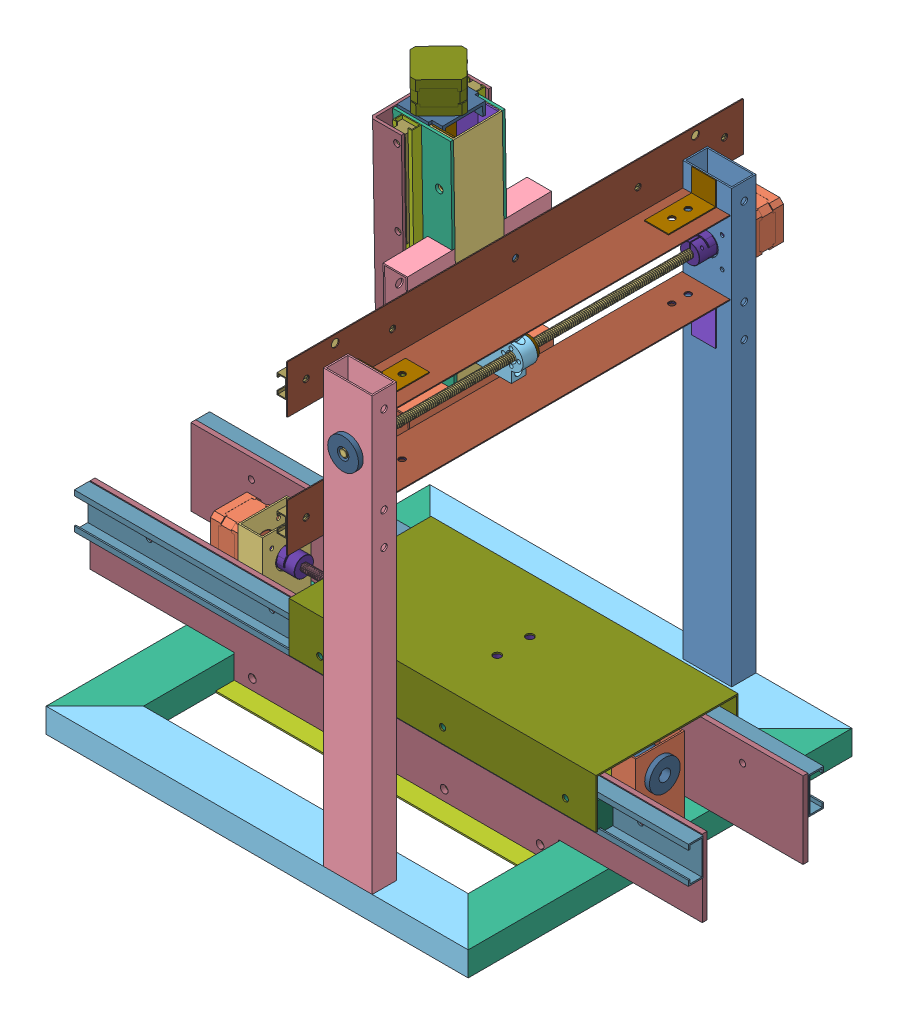
SolidWorks assembly cnc vr 3.0, configuration Predeterminado. Lengths in mm.
Overall size (640 636.76 475).
65 component instances, 40 part files, 107 mates.
Components (placement in the parent):
- Ensamblaje1-1: Ensamblaje1 [Predeterminado] at (-134.9886 -175.6891 185.1886) x (1 0 0) z (0 -1 0) size (445 405 475.4)
  - soporte vertical base eje Y (motor)-1: soporte vertical base eje Y (motor) [Predeterminado] at (289.2 12.7 -12.7) x (1 0 0) z (0 0 -1) size (50.8 25.4 450)
  - soporte rodamiento eje X-1: soporte rodamiento eje X [Predeterminado] at (401.9 200 -12.7) x (0 1 0) z (0 0 -1) size (50.8 25.4 85)
  - soporte motor eje X-1: soporte motor eje X [Predeterminado] at (12.7 200 -12.7) x (0 1 0) z (0 0 -1) size (50.8 25.4 90)
  - soporte vertical base eje Y (rodamiento)-1: soporte vertical base eje Y (rodamiento) [Predeterminado] at (289.2 387.3 -12.7) x (1 0 0) z (0 0 -1) size (50.8 25.4 450)
  - base 2x1 laterales-1: base 2x1 laterales [Predeterminado] at (-25.4 374.6 0) x (0 -1 0) z (1 0 0) size (50.8 25.4 440)
  - base 2x1 frontal-1: base 2x1 frontal [Predeterminado] at (389.2 0 0) x (-1 0 0) z (0 0 -1) size (50.8 400 25.4)
  - soporte transvarsal base-1: soporte transvarsal base [Predeterminado] at (25.4 151.5 12.7) x (0 -1 0) z (1 0 0) size (25.4 25.4 338.4)
  - base 2x1 laterales-2: base 2x1 laterales [Predeterminado] at (414.6 25.4 0) x (0 1 0) z (-1 0 0) size (50.8 25.4 440)
  - soporte transvarsal base-2: soporte transvarsal base [Predeterminado] at (363.8 248.5 12.7) x (0 1 0) z (-1 0 0) size (25.4 25.4 338.4)
  - junta eje y-1: junta eje y [Predeterminado] at (298.8 26.4 -359.7) x (0 0 1) z (-1 0 0) size (50 50 25)
  - junta eje2 y-1: junta eje2 y [Predeterminado] at (273.8 26.4 -438.7) x (0 0 -1) z (1 0 0) size (25 50 25)
  - junta eje2 y-2: junta eje2 y [Predeterminado] at (298.8 373.6 -438.7) x (0 0 -1) z (-1 0 0) size (25 50 25)
  - junta eje y-2: junta eje y [Predeterminado] at (273.8 373.6 -359.7) x (0 0 1) z (1 0 0) size (50 50 25)
  - asiento de rodamiento-1: asiento de rodamiento [Predeterminado] at (384.2 200 -72.7) x (0 -1 0) z (1 0 0) size (32 32 35.4)
  - asiento de rodamiento-2: asiento de rodamiento [Predeterminado] at (289.2 369.6 -400.2) x (1 0 0) z (0 1 0) size (32 32 35.4)
  - base 2x1 frontal-2: base 2x1 frontal [Predeterminado] at origin size (50.8 400 25.4)
- Soporte eje Y^cnc vr 3.0-2: Soporte eje Y^cnc vr 3.0 [Predeterminado] at (127.8114 261.0109 147.6886) size (60 175 475) (virtual)
  - soporte eje Y-1: soporte eje Y [Predeterminado] at origin size (50 50 475)
  - soporte eje Y-2: soporte eje Y [Predeterminado] at (0 -75 475) x (1 0 0) z (0 0 -1) size (50 50 475)
  - riel eje Y-1: riel eje Y [Predeterminado] at (0 35 0) x (-1 0 0) z (0 0 1) size (10 20 475)
  - riel eje Y-2: riel eje Y [Predeterminado] at (0 -90 0) x (-1 0 0) z (0 0 1) size (10 20 475)
- base lateral-1: base lateral [Predeterminado] at (228.6114 -186.4891 330.1886) size (638 105 5)
- base lateral-2: base lateral [Predeterminado] at (228.6114 -186.4891 435.1886) size (638 105 5)
- Riel eje x-1: Riel eje x [Predeterminado] at (-260.3886 -101.4891 322.4386) x (0 0 -1) z (1 0 0) size (15.5 38 640)
- Riel eje x-2: Riel eje x [Predeterminado] at (379.6114 -101.4891 447.9386) x (0 0 1) z (-1 0 0) size (15.5 38 640)
- Riel interior eje x-1: Riel interior eje x [Predeterminado] at (-33.1112 -101.4891 322.4386) x (0 0 -1) z (1 0 0) size (16 35 320)
- Riel interior eje x-2: Riel interior eje x [Predeterminado] at (286.8888 -101.4891 447.9386) x (0 0 1) z (-1 0 0) size (16 35 320)
- eje x-1: eje x [Predeterminado] at (-33.1112 -91.438 385.0405) x (0 0 -1) z (1 0 0) size (148 51.5 320)
- nut soporte-1: nut soporte [Predeterminado] at (119.3888 -102.8891 385.1886) x (0 0 -1) z (1 0 0) size (48 48.9 15)
- nut-2: nut [Predeterminado] at (115.3888 -102.8891 385.1886) x (0 0 -1) z (1 0 0) size (21 21 15.64)
- Base eje Y^cnc vr 3.0-2: Base eje Y^cnc vr 3.0 [Predeterminado] at (126.8114 170.0109 331.1531) x (-1 0 0) z (0 0 1) size (76.9 278.42 152.92) (virtual)
  - Riel interior eje Y-1: Riel interior eje Y [Predeterminado] at origin size (12 18 150)
  - Riel interior eje Y-2: Riel interior eje Y [Predeterminado] at (0 -125 2.0819) size (12 18 150)
  - componente 1 base eje y-1: componente 1 base eje y [Predeterminado] at (24.7 8.7522 0.002) x (0 -0.999863 0.016522) z (0 0.016522 0.999863) size (50.8 25.4 150)
  - componente 2 base eje y-1: componente 2 base eje y [Predeterminado] at (24.7 -241.3744 79.1455) x (0 -0.016522 -0.999863) z (0 0.999863 -0.016522) size (50.8 25.4 226)
  - componente 3 base eje y-1: componente 3 base eje y [Predeterminado] at (24.7 -118.2305 2.1004) x (0 -0.999863 0.016522) z (0 0.016522 0.999863) size (50.8 25.4 49.6)
  - componente 3 base eje y-2: componente 3 base eje y [Predeterminado] at (24.7 -115.7522 152.0799) x (0 -0.999863 0.016522) z (0 -0.016522 -0.999863) size (50.8 25.4 49.6)
  - nut soporte eje Y-1: nut soporte eje Y [Predeterminado] at (-27 -54.0239 68.5486) x (0 -0.999863 0.016522) z (0 0.016522 0.999863) size (48 51.5 15)
  - nut-1: nut [Predeterminado] at (-27 -54.09 64.5491) x (-1 0 0) z (0 0.016522 0.999863) size (21 21 15.64)
- soporte eje Z-3: soporte eje Z [Predeterminado] at (114.8114 262.8748 379.4406) x (0 0.999863 0.016522) z (0 -0.016522 0.999863) size (276 60.4 3)
- soporte eje Z-4: soporte eje Z [Predeterminado] at (114.8114 261.9859 433.2333) x (0 0.999863 0.016522) z (0 -0.016522 0.999863) size (276 60.4 3)
- riel eje Z-3: riel eje Z [Predeterminado] at (64.4114 411.8545 381.9024) x (0 0.016522 -0.999863) z (0 -0.999863 -0.016522) size (10 20 276)
- riel eje Z-4: riel eje Z [Predeterminado] at (64.4114 134.9537 434.1345) x (0 -0.016522 0.999863) z (0 0.999863 0.016522) size (10 20 276)
- soporte eje Z motor (derecho)-1: soporte eje Z motor (derecho) [Predeterminado] at (90.9114 412.2801 386.4101) x (1 0 0) z (0 -0.999863 -0.016522) size (22.4 23.9 60)
- soporte eje Z motor (izq)-1: soporte eje Z motor (izq) [Predeterminado] at (90.9114 351.4985 433.2122) x (1 0 0) z (0 0.999863 0.016522) size (22.4 23.9 60)
- soporte eje z motor frontal-1: soporte eje z motor frontal [Predeterminado] at (100.4114 415.2549 387.9594) x (0 -0.016522 0.999863) z (0 -0.999863 -0.016522) size (52 44 13)
- soporte eje Z rodamiento-1: soporte eje Z rodamiento [Predeterminado] at (114.8114 135.0526 379.7288) x (0 -0.016522 0.999863) z (1 0 0) size (52 3 58.4)
- Riel interior eje Z-1: Riel interior eje Z [Predeterminado] at (83.4114 407.1 439.6318) x (0 -0.016522 0.999863) z (0 -0.999863 -0.016522) size (12 18 100)
- Riel interior eje Z-2: Riel interior eje Z [Predeterminado] at (83.4114 308.0852 379.1876) x (0 0.016522 -0.999863) z (0 0.999863 0.016522) size (12 18 100)
- eje Z-1: eje Z [Predeterminado] at (84.4114 408.2698 368.8414) x (0 -0.016522 0.999863) z (0 -0.999863 -0.016522) size (88.8 38 276)
- nut soporte eje Z-1: nut soporte eje Z [Predeterminado] at (74.4114 315.0984 408.7075) x (0 -0.016522 0.999863) z (0 -0.999863 -0.016522) size (48 37.5 15)
- nut-1: nut [Predeterminado] at (74.4114 319.0978 408.7735) x (1 0 0) z (0 -0.999863 -0.016522) size (21 21 15.64)
- asiento de rodamiento eje z-1: asiento de rodamiento eje z [Predeterminado] at (74.4114 133.6232 405.7087) x (1 0 0) z (0 0.999863 0.016522) size (28 28 15)
- nema 17-1: nema 17 [Predeterminado] at (74.4114 431.3825 410.629) x (0 -0.999863 -0.016522) z (0.709494 0.011643 -0.704615) size (56.5 42 42)
- CPJC20-RD-5-8-1: CPJC20-RD-5-8 [Default] at (74.4114 401.3866 410.1333) x (0 -0.999863 -0.016522) z (0.927601 -0.006172 0.373521) size (30 20 20)
- tornillo de potencia eje Z-2: tornillo de potencia eje Z [Predeterminado] at (74.4114 131.6234 405.6756) x (-0.961589 -0.004535 0.274455) z (0 0.999863 0.016522) size (9.26 8.06 251.99)
- rodamiento skf 8X22-1: rodamiento skf 8X22 [Predeterminado] at (74.4114 137.6226 405.7748) x (1 0 0) z (0 -0.999863 -0.016522) size (22 22 8)
- nema 17-2-1: nema 17-2 [Predeterminado] at (154.2114 224.5109 168.6886) x (0 0 1) z (-1 0 0) size (56.5 42 42)
- CPJC20-RD-5-8-2: CPJC20-RD-5-8 [Default] at (154.2114 224.5109 198.6886) x (0 0 1) z (-1 0 0) size (30 20 20)
- tornillo de potencia eje Y-1: tornillo de potencia eje Y [Predeterminado] at (154.2114 224.5109 590.1886) x (1 0 0) z (0 0 -1) size (9.26 8.02 374.13)
- nema 17-2-2: nema 17-2 [Predeterminado] at (-151.4886 -102.9891 385.1886) size (56.5 42 42)
- CPJC20-RD-5-8-3: CPJC20-RD-5-8 [Default] at (-121.4886 -102.9891 385.1886) x (1 0 0) z (0 0.52607 -0.850441) size (30 20 20)
- tornillo de potencia-1: tornillo de potencia [Predeterminado] at (278.5114 -102.8891 385.1886) x (0 -0.883869 0.467735) z (-1 0 0) size (9.26 8.1 385.02)
- rodamiento skf 8X22-2: rodamiento skf 8X22 [Predeterminado] at (264.2114 -102.9891 385.1886) x (0 0 -1) z (1 0 0) size (22 22 8)
Mates (geometry in assembly coordinates):
- Concéntrica55: concentric aligned: cylinder of Ensamblaje1-1/junta eje2 y-2 through (151.3114 264.0109 542.7886) axis (0 -1 0) radius 3.2; cylinder of Soporte eje Y^cnc vr 3.0-2/soporte eje Y-1 through (151.3114 263.0109 542.7886) axis (0 -1 0) radius 3.2
- Concéntrica56: concentric aligned: cylinder of Ensamblaje1-1/junta eje2 y-1 through (151.3114 264.0109 227.5886) axis (0 -1 0) radius 3.2; cylinder of Soporte eje Y^cnc vr 3.0-2/soporte eje Y-1 through (151.3114 263.0109 227.5886) axis (0 -1 0) radius 3.2
- Coincidente86: coincident anti-aligned: plane of Ensamblaje1-1/junta eje2 y-1 through (163.8114 262.0109 210.5886) normal (0 -1 0); plane of Soporte eje Y^cnc vr 3.0-2/soporte eje Y-1 through (128.8114 262.0109 622.6886) normal (0 1 0)
- Concéntrica57: concentric aligned: cylinder of Ensamblaje1-1/junta eje y-2 through (151.3114 183.0109 542.7886) axis (0 1 0) radius 3.2; cylinder of Soporte eje Y^cnc vr 3.0-2/soporte eje Y-2 through (151.3114 184.0109 542.7886) axis (0 1 0) radius 3.2
- Concéntrica58: concentric aligned: cylinder of Ensamblaje1-1/junta eje y-1 through (151.3114 183.0109 227.5886) axis (0 1 0) radius 3.2; cylinder of Soporte eje Y^cnc vr 3.0-2/soporte eje Y-2 through (151.3114 184.0109 227.5886) axis (0 1 0) radius 3.2
- Coincidente87: coincident anti-aligned: plane of Ensamblaje1-1/junta eje y-1 through (138.8114 185.0109 210.5886) normal (0 1 0); plane of Soporte eje Y^cnc vr 3.0-2/soporte eje Y-2 through (128.8114 185.0109 147.6886) normal (0 -1 0)
- Coincidente104: coincident aligned: plane of soporte eje Z motor (derecho)-1 through (90.9114 412.2801 386.4101) normal (0 0.999863 0.016522); plane of soporte eje Z motor (izq)-1 through (90.9114 411.4903 434.2035) normal (0 0.999863 0.016522)
- Coincidente105: coincident anti-aligned: plane of soporte eje Z motor (derecho)-1 through (90.9114 351.8934 409.3155) normal (0 -0.016522 0.999863); plane of soporte eje Z motor (izq)-1 through (90.9114 411.8852 410.3068) normal (0 0.016522 -0.999863)
- Coincidente106: coincident aligned: plane of soporte eje Z motor (derecho)-1 through (92.4114 352.2635 386.9185) normal (1 0 0); plane of soporte eje Z motor (izq)-1 through (92.4114 411.5151 432.7038) normal (1 0 0)
- Concéntrica67: concentric anti-aligned: cylinder of soporte eje Z-3 through (74.4114 401.8063 384.7368) axis (0 0.016522 -0.999863) radius 3.2; cylinder of riel eje Z-3 through (74.4114 401.8889 379.7375) axis (0 -0.016522 0.999863) radius 3.2
- Concéntrica68: concentric anti-aligned: cylinder of soporte eje Z-3 through (74.4114 145.8412 380.5071) axis (0 0.016522 -0.999863) radius 3.2; cylinder of riel eje Z-3 through (74.4114 145.9238 375.5078) axis (0 -0.016522 0.999863) radius 3.2
- Coincidente100: coincident anti-aligned: plane of soporte eje Z-3 through (114.8114 262.8748 379.4406) normal (0 0.016522 -0.999863); plane of riel eje Z-3 through (64.4114 135.8922 377.3423) normal (0 -0.016522 0.999863)
- Concéntrica69: concentric aligned: cylinder of soporte eje Z-4 through (74.4114 400.9174 438.5294) axis (0 0.016522 -0.999863) radius 3.2; cylinder of riel eje Z-4 through (74.4114 400.8843 440.5292) axis (0 0.016522 -0.999863) radius 3.2
- Concéntrica70: concentric aligned: cylinder of soporte eje Z-4 through (74.4114 144.9523 434.2998) axis (0 0.016522 -0.999863) radius 3.2; cylinder of riel eje Z-4 through (74.4114 144.9193 436.2995) axis (0 0.016522 -0.999863) radius 3.2
- Coincidente101: coincident anti-aligned: plane of soporte eje Z-4 through (114.8114 261.9364 436.2329) normal (0 -0.016522 0.999863); plane of riel eje Z-4 through (64.4114 410.916 438.6947) normal (0 0.016522 -0.999863)
- Coincidente120: coincident anti-aligned: plane of soporte eje Z motor (derecho)-1 through (92.4114 352.2635 386.9185) normal (0 -0.016522 0.999863); plane of soporte eje z motor frontal-1 through (100.4114 412.2553 387.9099) normal (0 0.016522 -0.999863)
- Coincidente121: coincident anti-aligned: plane of soporte eje Z motor (izq)-1 through (92.4114 411.5151 432.7038) normal (1 0 0); plane of soporte eje z motor frontal-1 through (92.4114 401.5164 432.5385) normal (-1 0 0)
- Coincidente122: coincident anti-aligned: plane of soporte eje Z motor (izq)-1 through (90.9114 411.4903 434.2035) normal (0 0.999863 0.016522); plane of soporte eje z motor frontal-1 through (100.4114 412.2553 387.9099) normal (0 -0.999863 -0.016522)
- Coincidente127: coincident anti-aligned: plane of Soporte eje Y^cnc vr 3.0-2/riel eje Y-2 through (126.8114 170.0109 622.6886) normal (-1 0 0); plane of Base eje Y^cnc vr 3.0-2/Riel interior eje Y-1 through (126.8114 170.0109 481.1531) normal (1 0 0)
- Coincidente128: coincident anti-aligned: plane of Soporte eje Y^cnc vr 3.0-2/riel eje Y-2 through (118.8114 170.0109 622.6886) normal (0 -1 0); plane of Base eje Y^cnc vr 3.0-2/Riel interior eje Y-1 through (118.8114 170.0109 481.1531) normal (0 1 0)
- Coincidente129: coincident anti-aligned: plane of Soporte eje Y^cnc vr 3.0-2/riel eje Y-1 through (126.8114 295.0109 622.6886) normal (-1 0 0); plane of Base eje Y^cnc vr 3.0-2/Riel interior eje Y-2 through (126.8114 295.0109 483.235) normal (1 0 0)
- Coincidente130: coincident anti-aligned: plane of Soporte eje Y^cnc vr 3.0-2/riel eje Y-1 through (118.8114 295.0109 622.6886) normal (0 -1 0); plane of Base eje Y^cnc vr 3.0-2/Riel interior eje Y-2 through (118.8114 295.0109 483.235) normal (0 1 0)
- Coincidente131: coincident anti-aligned: plane of Base eje Y^cnc vr 3.0-2/componente 1 base eje y-1 through (114.8114 133.3839 480.715) normal (0 -0.999863 -0.016522); plane of soporte eje Z rodamiento-1 through (114.8114 135.0526 379.7288) normal (0 0.999863 0.016522)
- Coincidente132: coincident aligned: plane of Base eje Y^cnc vr 3.0-2/componente 1 base eje y-1 through (114.8114 133.3839 480.715) normal (1 0 0); plane of soporte eje Z rodamiento-1 through (114.8114 132.053 379.6792) normal (1 0 0)
- Coincidente133: coincident anti-aligned: plane of Base eje Y^cnc vr 3.0-2/componente 2 base eje y-1 through (90.9114 185.0212 430.4613) normal (1 0 0); plane of soporte eje Z motor (izq)-1 through (90.9114 411.4903 434.2035) normal (-1 0 0)
- Coincidente134: coincident anti-aligned: plane of Base eje Y^cnc vr 3.0-2/componente 2 base eje y-1 through (90.9114 185.0212 430.4613) normal (0 0.016522 -0.999863); plane of soporte eje Z motor (izq)-1 through (90.9114 411.4903 434.2035) normal (0 -0.016522 0.999863)
- Concéntrica85: concentric aligned: cylinder of Base eje Y^cnc vr 3.0-2/componente 2 base eje y-1 through (102.1114 361.469 435.0772) axis (0 0.016522 -0.999863) radius 4; cylinder of soporte eje Z-4 through (102.1114 361.4228 437.8768) axis (0 0.016522 -0.999863) radius 4
- Concéntrica86: concentric aligned: cylinder of Base eje Y^cnc vr 3.0-2/componente 2 base eje y-1 through (102.1114 223.4879 432.7971) axis (0 0.016522 -0.999863) radius 4; cylinder of soporte eje Z-4 through (102.1114 223.4416 435.5968) axis (0 0.016522 -0.999863) radius 4
- Coincidente135: coincident anti-aligned: plane of Base eje Y^cnc vr 3.0-2/componente 2 base eje y-1 through (89.4114 184.9964 431.9611) normal (0 -0.016522 0.999863); plane of soporte eje Z-4 through (114.8114 261.9859 433.2333) normal (0 0.016522 -0.999863)
- Coincidente136: coincident anti-aligned: plane of Base eje Y^cnc vr 3.0-2/componente 2 base eje y-1 through (89.4114 185.8358 381.168) normal (0 0.016522 -0.999863); plane of soporte eje Z-3 through (114.8114 262.8253 382.4402) normal (0 -0.016522 0.999863)
- Concéntrica87: concentric anti-aligned: cylinder of Base eje Y^cnc vr 3.0-2/componente 2 base eje y-1 through (102.1114 361.469 435.0772) axis (0 0.016522 -0.999863) radius 4; cylinder of soporte eje Z motor (izq)-1 through (102.1114 361.5302 431.3777) axis (0 -0.016522 0.999863) radius 4
- Distancia5: distance = 26 mm anti-aligned: plane of Base eje Y^cnc vr 3.0-2/componente 2 base eje y-1; plane of soporte eje Z rodamiento-1
- Coincidente137: coincident anti-aligned: plane of Base eje Y^cnc vr 3.0-2/componente 3 base eje y-1 through (89.4114 262.0254 382.427) normal (-1 0 0); plane of soporte eje Z-3 through (89.4114 312.8184 383.2663) normal (1 0 0)
- Coincidente138: coincident anti-aligned: plane of Base eje Y^cnc vr 3.0-2/componente 3 base eje y-1 through (114.8114 312.8184 383.2663) normal (0 0.999863 0.016522); plane of soporte eje Z-3 through (114.8114 312.8184 383.2663) normal (0 -0.999863 -0.016522)
- Coincidente139: coincident anti-aligned: plane of riel eje Z-4 through (65.4114 410.8995 439.6945) normal (0 -0.016522 0.999863); plane of Riel interior eje Z-1 through (83.4114 307.1137 437.9795) normal (0 0.016522 -0.999863)
- Coincidente140: coincident anti-aligned: plane of riel eje Z-4 through (65.4114 410.7673 447.6934) normal (1 0 0); plane of Riel interior eje Z-1 through (65.4114 307.1137 437.9795) normal (-1 0 0)
- Coincidente141: coincident anti-aligned: plane of riel eje Z-3 through (65.4114 135.9087 376.3424) normal (0 0.016522 -0.999863); plane of Riel interior eje Z-2 through (83.4114 408.0715 380.8398) normal (0 -0.016522 0.999863)
- Coincidente142: coincident anti-aligned: plane of riel eje Z-3 through (83.4114 135.9087 376.3424) normal (-1 0 0); plane of Riel interior eje Z-2 through (83.4114 408.2037 372.8409) normal (1 0 0)
- Concéntrica88: concentric aligned: cylinder of Riel interior eje Z-2 through (74.4114 398.172 374.6754) axis (0 0.016522 -0.999863) radius 3.2; cylinder of eje Z-1 through (74.4114 396.8337 455.6643) axis (0 0.016522 -0.999863) radius 3.2
- Concéntrica89: concentric anti-aligned: cylinder of Riel interior eje Z-1 through (74.4114 317.0132 444.1439) axis (0 -0.016522 0.999863) radius 3.2; cylinder of eje Z-1 through (74.4114 316.8446 454.3425) axis (0 0.016522 -0.999863) radius 3.2
- Coincidente144: coincident anti-aligned: plane of Riel interior eje Z-2 through (68.4114 408.2698 368.8414) normal (0 0.016522 -0.999863); plane of eje Z-1 through (84.4114 132.3075 364.2813) normal (0 -0.016522 0.999863)
- Concéntrica90: concentric aligned: cylinder of eje Z-1 through (50.4114 307.3185 425.5812) axis (-1 0 0) radius 4; cylinder of nut soporte eje Z-1 through (86.9124 307.3185 425.5812) axis (-1 0 0) radius 4
- Concéntrica92: concentric aligned: cylinder of eje Z-1 through (50.4114 307.8803 391.5859) axis (-1 0 0) radius 4; cylinder of nut soporte eje Z-1 through (86.9124 307.8803 391.5859) axis (-1 0 0) radius 4
- Coincidente145: coincident anti-aligned: plane of eje Z-1 through (49.4114 132.3075 364.2813) normal (1 0 0); plane of nut soporte eje Z-1 through (49.4114 300.497 384.4629) normal (-1 0 0)
- Concéntrica93: concentric aligned: cylinder of nut soporte eje Z-1 through (74.4114 300.1004 408.4596) axis (0 0.999863 0.016522) radius 5.5; cylinder of nut-1 through (74.4114 306.0996 408.5588) axis (0 0.999863 0.016522) radius 5.5
- Concéntrica94: concentric aligned: cylinder of nut soporte eje Z-1 through (74.4114 299.9683 416.4585) axis (0 0.999863 0.016522) radius 2; cylinder of nut-1 through (74.4114 314.9662 416.7064) axis (0 0.999863 0.016522) radius 2
- Coincidente146: coincident anti-aligned: plane of nut soporte eje Z-1 through (74.4114 315.0984 408.7075) normal (0 0.999863 0.016522); plane of nut-1 through (74.4114 315.0984 408.7075) normal (0 -0.999863 -0.016522)
- Concéntrica95: concentric anti-aligned: cylinder of soporte eje Z rodamiento-1 through (74.4114 131.6234 405.6756) axis (0 0.999863 0.016522) radius 14; cylinder of asiento de rodamiento eje z-1 through (74.4114 143.6218 405.8739) axis (0 -0.999863 -0.016522) radius 14
- Distancia6: distance = 3 mm aligned: plane of soporte eje Z rodamiento-1 through (114.8114 132.053 379.6792) normal (0 -0.999863 -0.016522); plane of asiento de rodamiento eje z-1 through (74.4114 128.6239 405.6261) normal (0 -0.999863 -0.016522)
- Concéntrica102: concentric anti-aligned: cylinder of soporte eje z motor frontal-1 through (74.4114 411.8852 410.3068) axis (0 0.999863 0.016522) radius 11.5; cylinder of nema 17-1 through (74.4114 415.8846 410.3729) axis (0 -0.999863 -0.016522) radius 11
- Concéntrica104: concentric aligned: cylinder of soporte eje z motor frontal-1 through (74.4114 411.5347 431.5139) axis (0 0.999863 0.016522) radius 2; cylinder of nema 17-1 through (74.4114 412.5846 431.5313) axis (0 0.999863 0.016522) radius 2
- Concéntrica105: concentric aligned: cylinder of nema 17-1 through (74.4114 415.8846 410.3729) axis (0 -0.999863 -0.016522) radius 2.5; circle of CPJC20-RD-5-8-1
- Distancia7: distance = 10 mm anti-aligned: plane of nema 17-1 through (74.4114 391.388 409.9681) normal (0 -0.999863 -0.016522); plane of CPJC20-RD-5-8-1 through (79.9098 401.1764 422.8569) normal (0 0.999863 0.016522)
- Concéntrica107: concentric aligned: cylinder of CPJC20-RD-5-8-1 through (74.4114 371.3907 409.6377) axis (0 0.999863 0.016522) radius 4; circle of tornillo de potencia eje Z-2
- Distancia9: distance = 10 mm anti-aligned: plane of CPJC20-RD-5-8-1 through (87.2129 371.479 404.2968) normal (0 -0.999863 -0.016522); plane of tornillo de potencia eje Z-2 through (74.4114 381.3893 409.8029) normal (0 0.999863 0.016522)
- Coincidente156: coincident anti-aligned: plane of soporte eje z motor frontal-1 through (100.4114 415.2549 387.9594) normal (0 0.999863 0.016522); plane of nema 17-1 through (74.4114 414.8848 410.3564) normal (0 -0.999863 -0.016522)
- Concéntrica108: concentric aligned: cylinder of asiento de rodamiento eje z-1 through (74.4114 143.6218 405.8739) axis (0 -0.999863 -0.016522) radius 11; cylinder of rodamiento skf 8X22-1 through (74.4114 141.6221 405.8409) axis (0 -0.999863 -0.016522) radius 11
- Coincidente157: coincident anti-aligned: plane of asiento de rodamiento eje z-1 through (74.4114 133.6232 405.7087) normal (0 0.999863 0.016522); plane of rodamiento skf 8X22-1 through (74.4114 133.6232 405.7087) normal (0 -0.999863 -0.016522)
- Tornillo1: screw = 1 aligned: circle of nut-1; cylinder of tornillo de potencia eje Z-2 through (74.4114 381.3893 409.8029) axis (0 -0.999863 -0.016522) radius 4
- Distancia límite1: limit distance = 156.5 mm anti-aligned: plane of nut soporte eje Z-1 through (74.4114 300.1004 408.4596) normal (0 -0.999863 -0.016522); plane of asiento de rodamiento eje z-1 through (74.4114 143.6218 405.8739) normal (0 0.999863 0.016522)
- Concéntrica109: concentric aligned: cylinder of Ensamblaje1-1/soporte vertical base eje Y (motor)-1 through (154.2114 224.5109 184.5886) axis (0 0 1) radius 11.5; cylinder of nema 17-2-1 through (154.2114 224.5109 184.1886) axis (0 0 1) radius 11
- Concéntrica110: concentric anti-aligned: cylinder of Ensamblaje1-1/soporte vertical base eje Y (motor)-1 through (169.7114 209.0109 184.5886) axis (0 0 1) radius 2; cylinder of nema 17-2-1 through (169.7114 209.0109 187.1386) axis (0 0 -1) radius 2
- Concéntrica111: concentric anti-aligned: cylinder of nema 17-2-1 through (154.2114 224.5109 184.1886) axis (0 0 1) radius 2.5; cylinder of CPJC20-RD-5-8-2 through (154.2114 224.5109 208.6886) axis (0 0 -1) radius 2.5
- Distancia10: distance = 10 mm anti-aligned: plane of CPJC20-RD-5-8-2 through (144.3573 214.7609 198.6886) normal (0 0 -1); plane of nema 17-2-1 through (154.2114 224.5109 208.6886) normal (0 0 1)
- Coincidente158: coincident anti-aligned: plane of Ensamblaje1-1/soporte vertical base eje Y (motor)-1 through (128.8114 287.0109 185.1886) normal (0 0 -1); plane of nema 17-2-1 through (154.2114 224.5109 185.1886) normal (0 0 1)
- Concéntrica112: concentric anti-aligned: cylinder of CPJC20-RD-5-8-2 through (154.2114 224.5109 228.6886) axis (0 0 -1) radius 4; cylinder of tornillo de potencia eje Y-1 through (154.2114 224.5109 218.6886) axis (0 0 1) radius 4
- Distancia11: distance = 10 mm anti-aligned: plane of CPJC20-RD-5-8-2 through (144.3323 234.2481 228.6886) normal (0 0 1); plane of tornillo de potencia eje Y-1 through (154.2114 224.5109 218.6886) normal (0 0 -1)
- Concéntrica113: concentric anti-aligned: cylinder of Ensamblaje1-1/soporte motor eje X-1 through (-108.9886 -102.9891 385.1886) axis (-1 0 0) radius 11.5; cylinder of nema 17-2-2 through (-135.9886 -102.9891 385.1886) axis (1 0 0) radius 11
- Concéntrica114: concentric aligned: cylinder of Ensamblaje1-1/soporte motor eje X-1 through (-108.9886 -87.4891 400.6886) axis (-1 0 0) radius 2; cylinder of nema 17-2-2 through (-133.0386 -87.4891 400.6886) axis (-1 0 0) radius 2
- Concéntrica115: concentric aligned: cylinder of Ensamblaje1-1/soporte motor eje X-1 through (-108.9886 -87.4891 400.6886) axis (-1 0 0) radius 2; cylinder of nema 17-2-2 through (-133.0386 -87.4891 400.6886) axis (-1 0 0) radius 2
- Concéntrica116: concentric anti-aligned: cylinder of nema 17-2-2 through (-135.9886 -102.9891 385.1886) axis (1 0 0) radius 2.5; cylinder of CPJC20-RD-5-8-3 through (-111.4886 -102.9891 385.1886) axis (-1 0 0) radius 2.5
- Distancia12: distance = 10 mm anti-aligned: plane of CPJC20-RD-5-8-3 through (-121.4886 -89.5134 381.9375) normal (-1 0 0); plane of nema 17-2-2 through (-111.4886 -102.9891 385.1886) normal (1 0 0)
- Coincidente159: coincident anti-aligned: plane of Ensamblaje1-1/soporte motor eje X-1 through (-134.9886 -72.9891 359.7886) normal (-1 0 0); plane of nema 17-2-2 through (-134.9886 -102.9891 385.1886) normal (1 0 0)
- Distancia13: distance = 10 mm anti-aligned: plane of CPJC20-RD-5-8-3 through (-91.4886 -106.0729 371.6645) normal (1 0 0); plane of tornillo de potencia-1 through (-101.4886 -102.8891 385.1886) normal (-1 0 0)
- Concéntrica23: concentric anti-aligned: cylinder of Riel interior eje x-1 through (254.8888 -101.4891 320.6886) axis (0 0 -1) radius 3.2; cylinder of eje x-1 through (254.8888 -101.4891 309.1886) axis (0 0 1) radius 3.2
- Coincidente50: coincident anti-aligned: plane of Riel interior eje x-1 through (286.8888 -114.4891 312.6886) normal (0 0 -1); plane of eje x-1 through (286.8888 -116.2852 312.6886) normal (0 0 1)
- Concéntrica22: concentric aligned: cylinder of Riel interior eje x-2 through (-1.1112 -101.4891 449.6886) axis (0 0 1) radius 3.2; cylinder of eje x-1 through (-1.1112 -101.4891 309.1886) axis (0 0 1) radius 3.2
- Concéntrica24: concentric aligned: cylinder of eje x-1 through (126.8888 -66.9891 402.1886) axis (0 1 0) radius 4; cylinder of nut soporte-1 through (126.8888 -115.3901 402.1886) axis (0 1 0) radius 4
- Concéntrica25: concentric aligned: cylinder of eje x-1 through (126.8888 -66.9891 368.1886) axis (0 1 0) radius 4; cylinder of nut soporte-1 through (126.8888 -115.3901 368.1886) axis (0 1 0) radius 4
- Coincidente51: coincident anti-aligned: plane of eje x-1 through (286.8888 -66.4891 457.6886) normal (0 -1 0); plane of nut soporte-1 through (134.3888 -66.4891 409.1886) normal (0 1 0)
- Concéntrica26: concentric aligned: cylinder of nut soporte-1 through (134.3888 -102.8891 385.1886) axis (-1 0 0) radius 5.5; cylinder of nut-2 through (128.3888 -102.8891 385.1886) axis (-1 0 0) radius 5.5
- Concéntrica27: concentric aligned: cylinder of nut soporte-1 through (134.3888 -110.8891 385.1886) axis (-1 0 0) radius 2; cylinder of nut-2 through (119.3888 -110.8891 385.1886) axis (-1 0 0) radius 2
- Coincidente53: coincident anti-aligned: plane of nut soporte-1 through (119.3888 -102.8891 385.1886) normal (-1 0 0); plane of nut-2 through (119.3888 -102.8891 385.1886) normal (1 0 0)
- Concéntrica14: concentric anti-aligned: cylinder of base lateral-1 through (-196.3886 -101.4891 335.1886) axis (0 0 -1) radius 3.2; cylinder of Riel eje x-1 through (-196.3886 -101.4891 328.1886) axis (0 0 1) radius 3.2
- Concéntrica15: concentric anti-aligned: cylinder of base lateral-1 through (315.6114 -101.4891 335.1886) axis (0 0 -1) radius 3.2; cylinder of Riel eje x-1 through (315.6114 -101.4891 328.1886) axis (0 0 1) radius 3.2
- Coincidente44: coincident anti-aligned: plane of base lateral-1 through (228.6114 -186.4891 330.1886) normal (0 0 -1); plane of Riel eje x-1 through (379.6114 -120.4891 330.1886) normal (0 0 1)
- Concéntrica16: concentric aligned: cylinder of base lateral-2 through (-196.3886 -101.4891 440.1886) axis (0 0 -1) radius 3.2; cylinder of Riel eje x-2 through (-196.3886 -101.4891 442.1886) axis (0 0 -1) radius 3.2
- Concéntrica17: concentric aligned: cylinder of base lateral-2 through (315.6114 -101.4891 440.1886) axis (0 0 -1) radius 3.2; cylinder of Riel eje x-2 through (315.6114 -101.4891 442.1886) axis (0 0 -1) radius 3.2
- Coincidente45: coincident anti-aligned: plane of base lateral-2 through (228.6114 -186.4891 440.1886) normal (0 0 1); plane of Riel eje x-2 through (-260.3886 -120.4891 440.1886) normal (0 0 -1)
- Concéntrica118: concentric aligned: cylinder of Ensamblaje1-1/soporte transvarsal base-1 through (209.6114 -175.4891 337.1886) axis (0 0 -1) radius 4; cylinder of base lateral-1 through (209.6114 -175.4891 335.1886) axis (0 0 -1) radius 4
- Paralelo14: parallel aligned: cylinder of Ensamblaje1-1/soporte transvarsal base-1 through (-90.3886 -175.4891 337.1886) axis (0 0 -1) radius 4; cylinder of base lateral-1 through (-90.3886 -175.4891 335.1886) axis (0 0 -1) radius 4
- Coincidente164: coincident anti-aligned: plane of Ensamblaje1-1/soporte transvarsal base-1 through (228.8114 -186.8891 335.1886) normal (0 0 -1); plane of base lateral-1 through (228.6114 -186.4891 335.1886) normal (0 0 1)
- Concéntrica119: concentric aligned: cylinder of Ensamblaje1-1/soporte transvarsal base-1 through (-90.3886 -175.4891 337.1886) axis (0 0 -1) radius 4; cylinder of base lateral-1 through (-90.3886 -175.4891 335.1886) axis (0 0 -1) radius 4
- Concéntrica120: concentric anti-aligned: cylinder of Ensamblaje1-1/soporte transvarsal base-2 through (-90.3886 -175.4891 433.1886) axis (0 0 1) radius 4; cylinder of base lateral-2 through (-90.3886 -175.4891 440.1886) axis (0 0 -1) radius 4
- Paralelo15: parallel anti-aligned: cylinder of Ensamblaje1-1/soporte transvarsal base-2 through (209.6114 -175.4891 433.1886) axis (0 0 1) radius 4; cylinder of base lateral-2 through (209.6114 -175.4891 440.1886) axis (0 0 -1) radius 4
- Coincidente165: coincident anti-aligned: plane of Ensamblaje1-1/soporte transvarsal base-2 through (-109.5886 -186.8891 435.1886) normal (0 0 1); plane of base lateral-2 through (228.6114 -186.4891 435.1886) normal (0 0 -1)
- Concéntrica121: concentric anti-aligned: cylinder of Ensamblaje1-1/soporte transvarsal base-2 through (209.6114 -175.4891 433.1886) axis (0 0 1) radius 4; cylinder of base lateral-2 through (209.6114 -175.4891 440.1886) axis (0 0 -1) radius 4
- Coincidente166: coincident anti-aligned: plane of Riel eje x-1 through (379.6114 -83.9891 328.6886) normal (0 -1 0); plane of Riel interior eje x-1 through (286.8888 -83.9891 328.6886) normal (0 1 0)
- Coincidente167: coincident anti-aligned: plane of Riel eje x-1 through (379.6114 -118.9891 328.6886) normal (0 0 -1); plane of Riel interior eje x-1 through (286.8888 -118.9891 328.6886) normal (0 0 1)
- Coincidente168: coincident anti-aligned: plane of Riel eje x-2 through (-260.3886 -118.9891 441.6886) normal (0 0 1); plane of Riel interior eje x-2 through (-33.1112 -118.9891 441.6886) normal (0 0 -1)
- Coincidente169: coincident anti-aligned: plane of Riel eje x-2 through (-260.3886 -83.9891 441.6886) normal (0 -1 0); plane of Riel interior eje x-2 through (-33.1112 -83.9891 441.6886) normal (0 1 0)
- Tornillo5: screw = 1 anti-aligned: cylinder of nut-2 through (119.3888 -102.8891 385.1886) axis (-1 0 0) radius 3; cylinder of tornillo de potencia-1 through (-101.4886 -102.8891 385.1886) axis (1 0 0) radius 4
- Concéntrica122: concentric anti-aligned: cylinder of Ensamblaje1-1/asiento de rodamiento-1 through (268.2114 -102.9891 385.1886) axis (-1 0 0) radius 11; cylinder of rodamiento skf 8X22-2 through (260.2114 -102.9891 385.1886) axis (1 0 0) radius 11
- Coincidente170: coincident anti-aligned: plane of Ensamblaje1-1/asiento de rodamiento-1 through (268.2114 -102.9891 385.1886) normal (-1 0 0); plane of rodamiento skf 8X22-2 through (268.2114 -102.9891 385.1886) normal (1 0 0)
- Distancia límite2: limit distance = 206.8774 mm anti-aligned: plane of nut-2 through (115.3888 -102.8891 385.1886) normal (-1 0 0); plane of CPJC20-RD-5-8-3 through (-91.4886 -106.0729 371.6645) normal (1 0 0)
- Relación de posición de engranaje1: gear = 8 : 8 mm: circle of tornillo de potencia-1; circle of CPJC20-RD-5-8-3
- Relación de posición de engranaje2: gear = 8 : 8 mm: circle of tornillo de potencia eje Z-2; circle of CPJC20-RD-5-8-1
